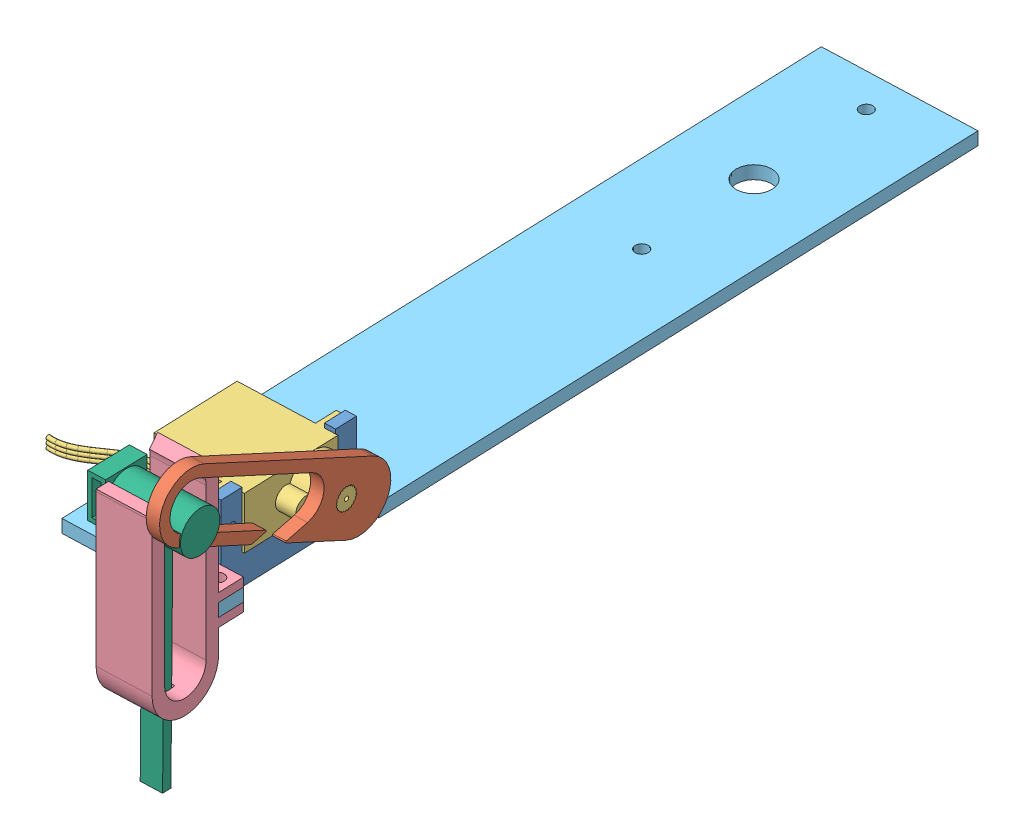
SolidWorks assembly Assem1, configuration Default. Lengths in mm.
Overall size (48.91 71.15 202.29).
6 component instances, 6 part files, 14 mates.
Components (placement in the parent):
- tempat servo spidol-1: tempat servo spidol [Default] at (114.4005 114.4665 201.4568) x (0.036544 0 0.999332) z (-0.999332 0 0.036544) size (32.5 20 20.5)
- penggerak pulpen-2: penggerak pulpen [Default] at (122.0432 117.4168 191.5381) x (0.032953 0.432246 0.901153) z (-0.999332 0 0.036544) size (60 15 3)
- Servo Motor SG90 1PC.stp-2: Servo Motor SG90 1PC.stp [Default] at (92.4152 120.4665 202.2607) x (0 1 0) z (0.999332 0 -0.036544) size (12 33.08 46.7)
- tempat spidol vertikal-1: tempat spidol vertikal [Default] at (108.011 119.9665 231.9606) x (-0.036544 0 -0.999332) z (0.999332 0 -0.036544) size (22 47.21 12.5)
- Arm 2 [FIX]-1: Arm 2 [FIX] [Default] at (104.0643 109.4665 124.0328) x (-0.036544 0 -0.999332) z (0.999332 0 -0.036544) size (182.5 3 35)
- penyambung penggerak-3: penyambung penggerak [Default] at (123.7484 132.3058 231.3277) x (0.036542 0.008863 0.999293) z (-0.999332 0 0.036544) size (10 60 20.59)
Mates (geometry in assembly coordinates):
- Concentric1: concentric anti-aligned: cylinder of tempat spidol vertikal-1 through (110.607 93.9665 220.8583) axis (0 1 0) radius 1.5; cylinder of Arm 2 [FIX]-1 through (110.607 112.4665 220.8583) axis (0 -1 0) radius 1.5
- Coincident1: coincident anti-aligned: plane of tempat servo spidol-1 through (93.9142 109.4665 202.2059) normal (0 1 0); plane of Arm 2 [FIX]-1 through (104.0643 109.4665 124.0328) normal (0 -1 0)
- Coincident2: coincident anti-aligned: plane of tempat servo spidol-1 through (93.9142 112.4665 202.2059) normal (0 -1 0); plane of Arm 2 [FIX]-1 through (104.0643 112.4665 124.0328) normal (0 1 0)
- Concentric2: concentric anti-aligned: cylinder of tempat servo spidol-1 through (98.4084 107.4665 188.2824) axis (0 1 0) radius 1.5; cylinder of Arm 2 [FIX]-1 through (98.4084 112.4665 188.2824) axis (0 -1 0) radius 1.5
- Concentric3: concentric anti-aligned: cylinder of tempat servo spidol-1 through (105.4037 107.4665 188.0266) axis (0 1 0) radius 1.5; cylinder of Arm 2 [FIX]-1 through (105.4037 112.4665 188.0266) axis (0 -1 0) radius 1.5
- Concentric4: concentric aligned: circle of tempat servo spidol-1; circle of Servo Motor SG90 1PC.stp-2
- Concentric5: concentric anti-aligned: circle of tempat servo spidol-1; circle of Servo Motor SG90 1PC.stp-2
- Coincident3: coincident anti-aligned: plane of tempat servo spidol-1 through (111.9022 114.4665 201.5481) normal (-0.999332 0 0.036544); plane of Servo Motor SG90 1PC.stp-2 through (111.9022 120.4665 201.5481) normal (0.999332 0 -0.036544)
- Concentric6: concentric anti-aligned: cylinder of tempat spidol vertikal-1 through (117.1027 93.9665 220.6208) axis (0 1 0) radius 1.5; cylinder of Arm 2 [FIX]-1 through (117.1027 112.4665 220.6208) axis (0 -1 0) radius 1.5
- Coincident4: coincident anti-aligned: plane of penggerak pulpen-2 through (119.0452 117.4168 191.6477) normal (-0.999332 0 0.036544); plane of Servo Motor SG90 1PC.stp-2 through (119.3241 120.4665 199.2754) normal (0.999332 0 -0.036544)
- Coincident5: coincident anti-aligned: plane of tempat spidol vertikal-1 through (119.991 112.4665 217.5132) normal (0 -1 0); plane of Arm 2 [FIX]-1 through (104.0643 112.4665 124.0328) normal (0 1 0)
- Concentric7: concentric aligned: circle of penggerak pulpen-2; circle of Servo Motor SG90 1PC.stp-2
- Coincident10: coincident anti-aligned: line of tempat spidol vertikal-1 through (111.5543 97.6253 233.0819) axis (0.999332 0 -0.036544); plane of penyambung penggerak-3 through (111.8108 77.3168 233.2526) normal (0.036542 0.008863 0.999293)
- Width1: width anti-aligned: plane of tempat spidol vertikal-1 through (117.0507 93.9665 232.8809) normal (-0.999332 0 0.036544); plane of penyambung penggerak-3 through (111.5543 93.9665 233.0819) normal (0.999332 0 -0.036544); plane of tempat spidol vertikal-1 through (116.8074 77.3168 233.0699) normal (0.999332 0 -0.036544); plane of penyambung penggerak-3 through (111.8108 77.3168 233.2526) normal (-0.999332 0 0.036544)
